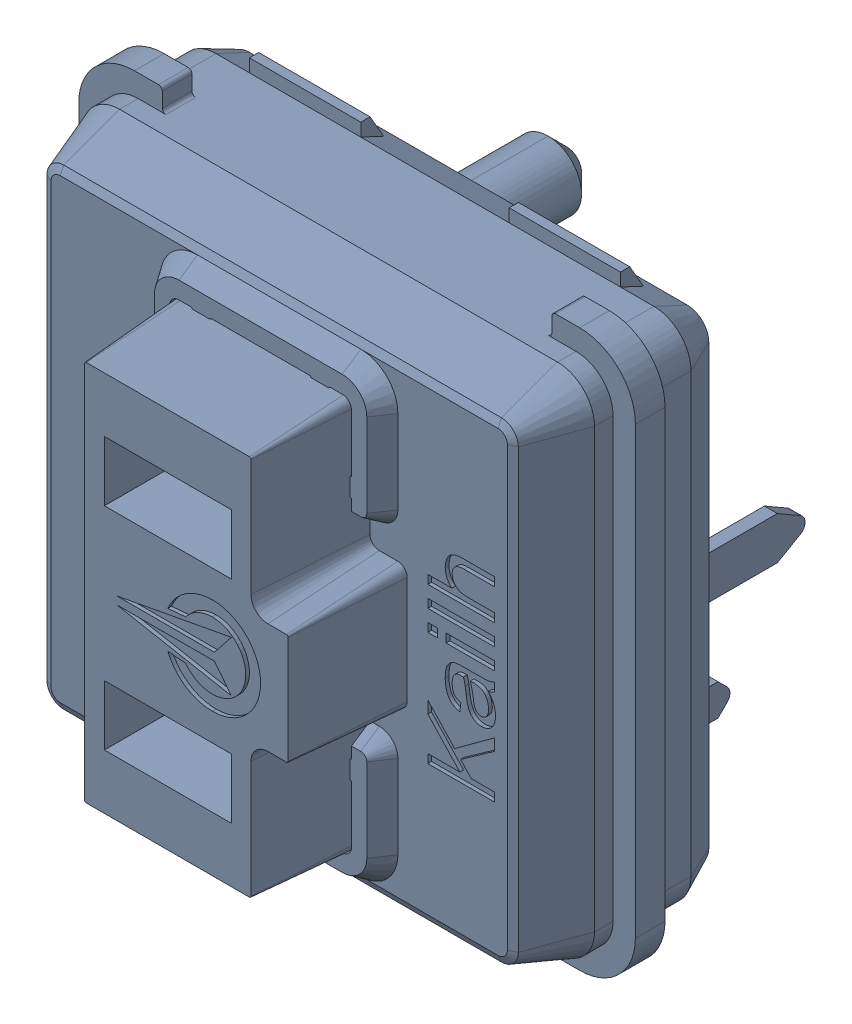
SolidWorks assembly SW6_1.step, configuration Default. Lengths in mm.
Overall size (15 15 11.1).
2 component instances, 2 part files, 0 mates.
Components (placement in the parent):
- Kailh LP Choc Burnt Orange_1.step-3: Kailh LP Choc Burnt Orange_1.step [Default] at (465.9499 283.4846 2.7) x (1 0 0) z (0 -1 0) size (15 11.1 15)
- WS2812-2020_1.step-3: WS2812-2020_1.step [Default] at (461.3087 283.5912 0.3) x (0 1 0) z (1 0 0) size (2.2 0.86 2)
